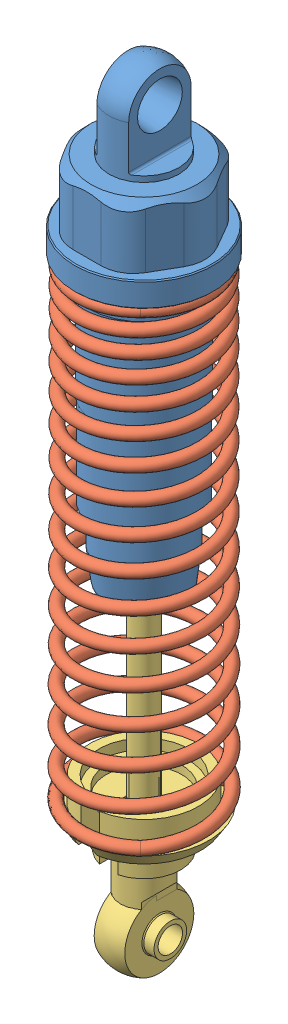
SolidWorks assembly RC Damper HSP 296004, configuration Default. Lengths in mm.
Overall size (24.27 96.92 24.27).
3 component instances, 3 part files, 5 mates.
Components (placement in the parent):
- Damper Body --1: Damper Body - [Default] at (-61.7292 12.4997 14.5362) size (16.95 56.5 16.95)
- RC Spring - 58.5mm compressed - 62mm free lenght-1: RC Spring - 58.5mm compressed - 62mm free lenght [Default] at (-61.7292 -24.0003 14.5362) x (0.734117 0 -0.679023) z (0.679023 0 0.734117) size (17.14 58.65 17.21)
- Shaft --1: Shaft - [Default] at (-61.7292 6.4997 14.5362) size (15.85 48 15.77)
Mates (geometry in assembly coordinates):
- Concentric2: concentric aligned: cylinder of Damper Body --1 through (-61.7292 50.4997 14.5362) axis (0 1 0) radius 5.9; line of RC Spring - 58.5mm compressed - 62mm free lenght-1 through (-61.7292 -24.7003 14.5362) axis (0 1 0)
- Tangent3: tangent: plane of Damper Body --1 through (-61.7292 33.7997 6.1862) normal (0 -1 0); circle of RC Spring - 58.5mm compressed - 62mm free lenght-1
- Concentric3: concentric anti-aligned: line of RC Spring - 58.5mm compressed - 62mm free lenght-1 through (-61.7292 -24.7003 14.5362) axis (0 1 0); cylinder of Shaft --1 through (-61.7292 -37.5003 14.5362) axis (0 -1 0) radius 1.5
- Parallel1: parallel aligned: plane of Damper Body --1 through (-63.6792 54.2497 14.5362) normal (-1 0 0); plane of Shaft --1 through (-63.6042 6.4997 14.5362) normal (-1 0 0)
- Shock Travel: limit distance = 88 mm: point of Shaft --1; point of Damper Body --1
